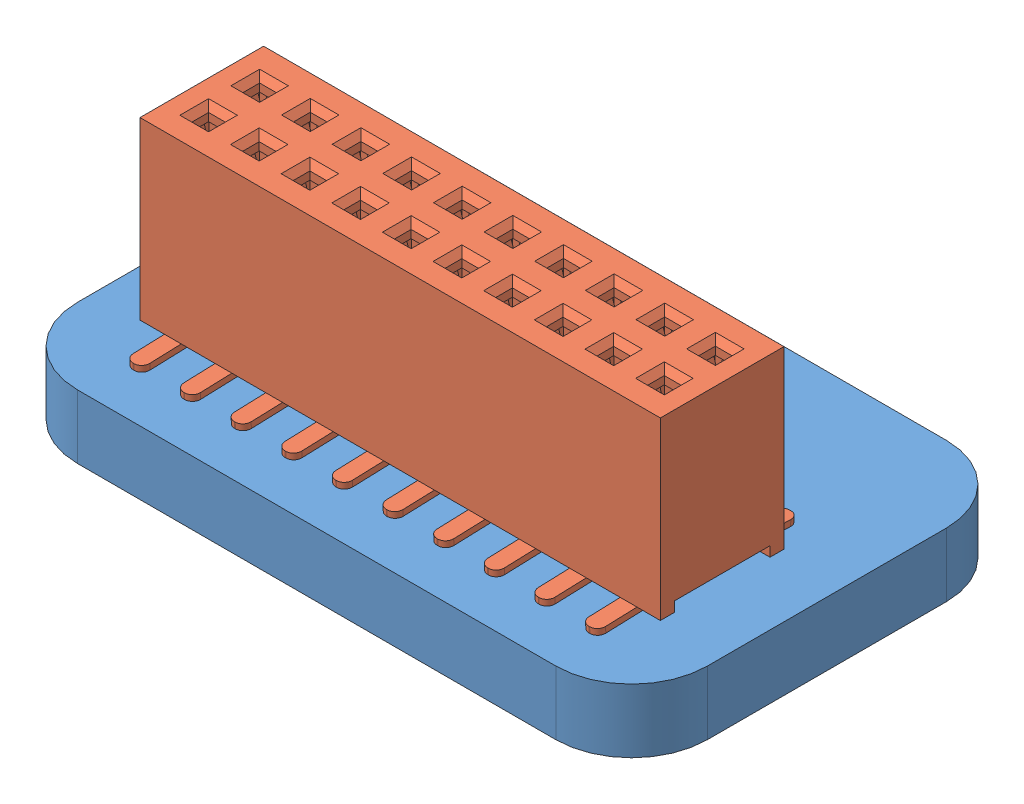
SolidWorks assembly BackplaneDebugCap_1U, configuration Default. Lengths in mm.
Overall size (15.8 6.2 9.8).
2 component instances, 2 part files, 3 mates.
Components (placement in the parent):
- BackplaneDebugCapBoard_1U-1: BackplaneDebugCapBoard_1U [Default] at origin size (15.8 1.6 9.8)
- m50-3101045_asm-1: m50-3101045_asm [Default] at (-6.35 6.1985 0) size (13.05 4.6 5.05)
Mates (geometry in assembly coordinates):
- Coincident5: coincident aligned: plane of m50-3101045_asm-1 through (-6.35 6.1985 0) normal (0 0 1)
- Coincident6: coincident: plane of BackplaneDebugCapBoard_1U-1 through (0 1.6 0) normal (0 1 0); line of m50-3101045_asm-1 through (-4.435 1.6 -2.5174) axis (-1 0 0)
- Coincident7: coincident aligned: plane of m50-3101045_asm-1 through (0 6.1985 0) normal (1 0 0)
